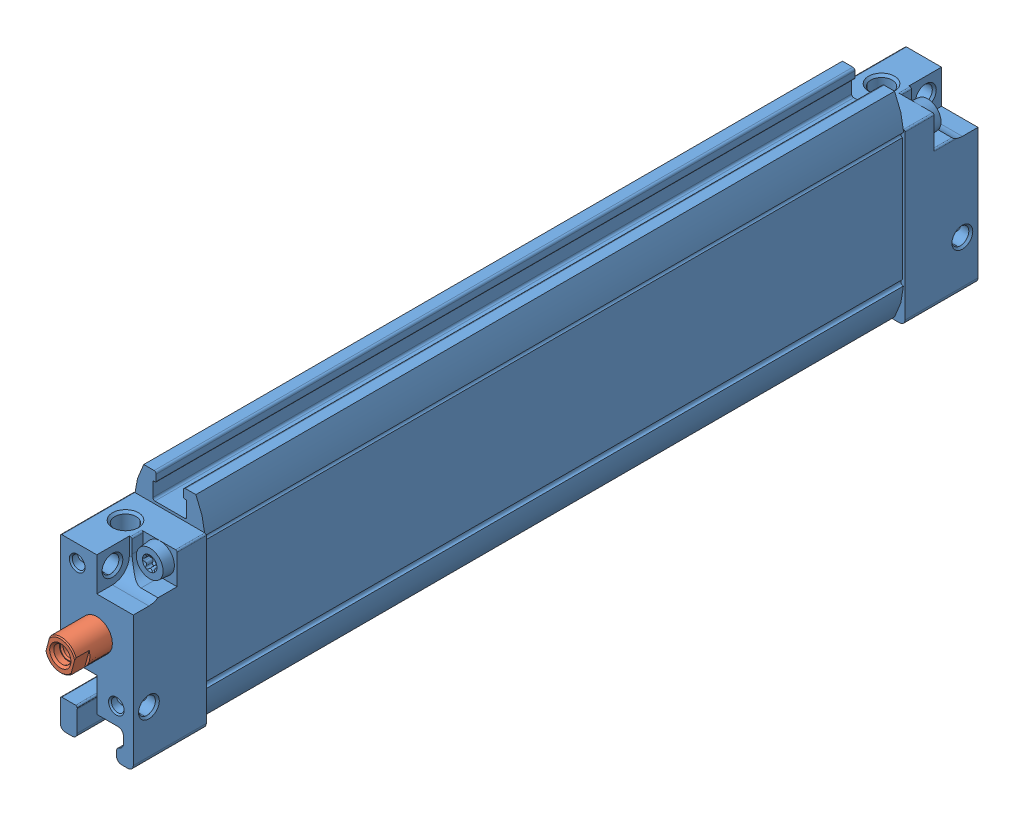
SolidWorks assembly 164008_DZF_12_100_P_A____0_, configuration Default. Lengths in mm.
Overall size (14 38 169.13).
4 component instances, 3 part files, 3 mates.
Components (placement in the parent):
- 164008_DZF_12_100_P_A____ZR_-1: 164008_DZF_12_100_P_A____ZR_ [Default] at origin size (14 38 162)
- 164008_DZF_12_100_P_A____KS_-1: 164008_DZF_12_100_P_A____KS_ [Default] at origin size (9 18 145.15)
- DIN_913___M5x5-1: DIN_913___M5x5 [Default] at (-2.5 4.75 -162) x (0 0 1) z (-1 0 0) size (5.13 5 5)
- DIN_913___M5x5-2: DIN_913___M5x5 [Default] at (2.5 -4.75 -162) x (0 0 1) z (-1 0 0) size (5.13 5 5)
Mates (geometry in assembly coordinates):
- LimitDistance2: limit distance = 0 mm aligned: plane of 164008_DZF_12_100_P_A____ZR_-1 through (0 0 -138.15) normal (0 0 1); plane of 164008_DZF_12_100_P_A____KS_-1 through (0 0 -138.15) normal (0 0 1)
- Coincident1: coincident aligned: line of 164008_DZF_12_100_P_A____ZR_-1 through (0 0 80.9) axis (0 0 -1); line of 164008_DZF_12_100_P_A____KS_-1 through (0 0 80.9) axis (0 0 -1)
- Angle3: planar angle = 0 rad aligned: plane of 164008_DZF_12_100_P_A____KS_-1 through (0 0 0) normal (1 0 0); plane of 164008_DZF_12_100_P_A____ZR_-1 through (0 0 0) normal (1 0 0)
